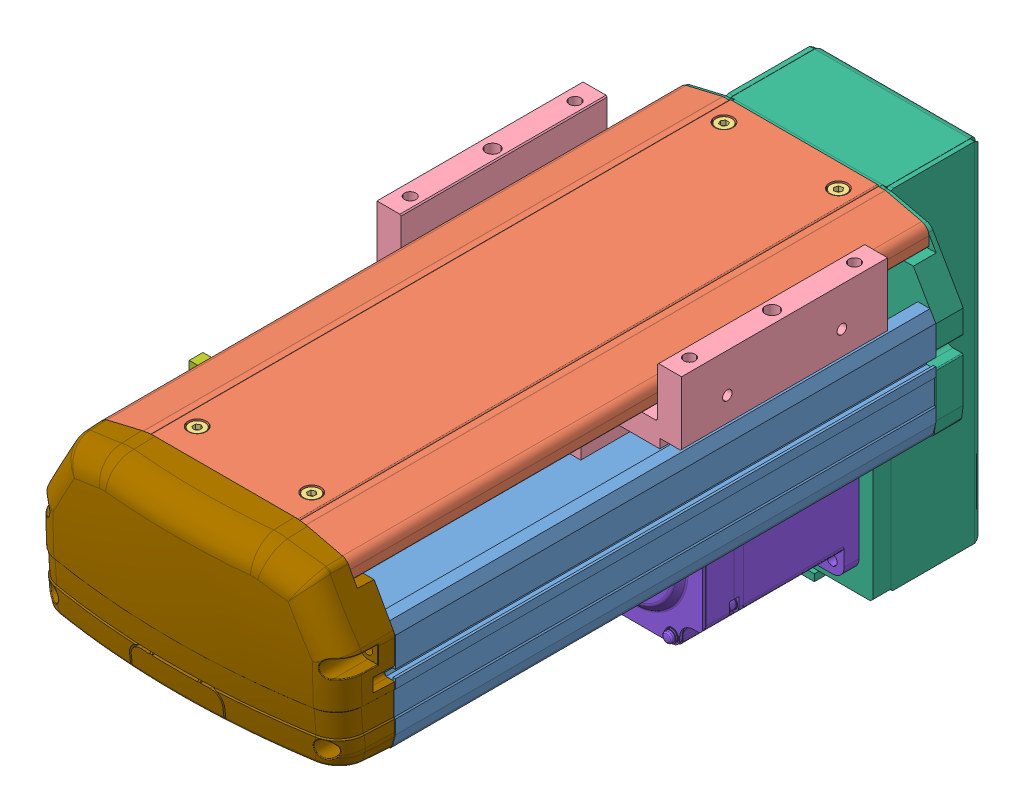
SolidWorks assembly S13-BM-200W, configuration 默认. Lengths in mm.
Overall size (190.95 160.5 348.72).
14 component instances, 9 part files, 41 mates.
Components (placement in the parent):
- S13-BL底座^S13-BM-200W-2: S13-BL底座^S13-BM-200W [默认] at origin size (135 48 259) (virtual)
- S13-BL上盖^S13-BM-200W-2: S13-BL上盖^S13-BM-200W [默认] at (0 61 116.5) size (109 12.5 253) (virtual)
- 内六角圆柱头螺钉M4×8[GB／T70．1-2000]^S13-BM-200W-5: 内六角圆柱头螺钉M4×8[GB／T70．1-2000]^S13-BM-200W [默认] at (-25 73.2 0) x (0 -1 0) z (-0.993621 0 -0.11277) size (12 7 7) (virtual)
- 内六角圆柱头螺钉M4×8[GB／T70．1-2000]^S13-BM-200W-6: 内六角圆柱头螺钉M4×8[GB／T70．1-2000]^S13-BM-200W [默认] at (25 73.2 0) x (0 -1 0) z (0.295931 0 -0.955209) size (12 7 7) (virtual)
- 内六角圆柱头螺钉M4×8[GB／T70．1-2000]^S13-BM-200W-7: 内六角圆柱头螺钉M4×8[GB／T70．1-2000]^S13-BM-200W [默认] at (-25 73.2 230) x (0 -1 0) z (0.881053 0 0.473018) size (12 7 7) (virtual)
- 内六角圆柱头螺钉M4×8[GB／T70．1-2000]^S13-BM-200W-8: 内六角圆柱头螺钉M4×8[GB／T70．1-2000]^S13-BM-200W [默认] at (25 73.2 230) x (0 -1 0) z (0.809751 0 0.586773) size (12 7 7) (virtual)
- S13-BC 滑座^S13-BM-200W-2: S13-BC 滑座^S13-BM-200W [默认] at (-1.3936 35.7784 20) size (133 62 90) (virtual)
- 复件 外置感应片ST14-17^S13-BM-200W-2: 复件 外置感应片ST14-17^S13-BM-200W [默认] at (-67.5 55 65) x (0 0 1) z (-1 0 0) size (70 30.4 7.7) (virtual)
- 复件 S13-14-BM电机板罩壳^S13-BM-200W-3: 复件 S13-14-BM电机板罩壳^S13-BM-200W [默认] at (34.6396 0 343.3649) x (-0.923728 0 0.383049) z (0 -1 0) size (129.3 86.61 155.28) (virtual)
- 复件 光电开关EE-SX672^S13-BM-200W-4: 复件 光电开关EE-SX672^S13-BM-200W [默认] at (-67.5 19.7 49) x (0 0 1) z (-1 0 0) size (26 25 13) (virtual)
- 复件 光电开关EE-SX672^S13-BM-200W-5: 复件 光电开关EE-SX672^S13-BM-200W [默认] at (-67.5 19.7 75) x (0 0 1) z (-1 0 0) size (26 25 13) (virtual)
- 复件 光电开关EE-SX672^S13-BM-200W-6: 复件 光电开关EE-SX672^S13-BM-200W [默认] at (-67.5 19.7 172) x (0 0 1) z (-1 0 0) size (26 25 13) (virtual)
- 复件 复件 松下200W电机MHMF022L1U22^S13-BM-200W-2: 复件 复件 松下200W电机MHMF022L1U22^S13-BM-200W [默认] at (0 -41.1 -4) x (0 0 -1) z (0 1 0) size (101 149.2 60) (virtual)
- 复件 13-14塑胶端盖 ^S13-BM-200W-2: 复件 13-14塑胶端盖 ^S13-BM-200W [默认] at (0 1 256) x (-1 0 0) z (0 0 -1) size (134.5 73.26 31.04) (virtual)
Mates (geometry in assembly coordinates):
- 重合169: coincident: plane of S13-BL上盖^S13-BM-200W-2 through (-25 69.2 0) normal (0 1 0); plane of 内六角圆柱头螺钉M4×8[GB／T70．1-2000]^S13-BM-200W-5 through (-25.3947 69.2 3.4777) normal (0 -1 0)
- 同心160: concentric: cylinder of 内六角圆柱头螺钉M4×8[GB／T70．1-2000]^S13-BM-200W-5 through (-25 73.2 0) axis (0 1 0) radius 3.5; cylinder of S13-BL上盖^S13-BM-200W-2 through (-25 69.2 0) axis (0 1 0) radius 4
- 同心161: concentric: cylinder of 内六角圆柱头螺钉M4×8[GB／T70．1-2000]^S13-BM-200W-6 through (25 73.2 0) axis (0 1 0) radius 3.5; cylinder of S13-BL上盖^S13-BM-200W-2 through (25 69.2 0) axis (0 1 0) radius 4
- 重合171: coincident: plane of S13-BL上盖^S13-BM-200W-2 through (25 69.2 0) normal (0 1 0); circle of 内六角圆柱头螺钉M4×8[GB／T70．1-2000]^S13-BM-200W-6
- 重合189: coincident: plane of S13-BL上盖^S13-BM-200W-2 through (25 69.2 230) normal (0 1 0); plane of 内六角圆柱头螺钉M4×8[GB／T70．1-2000]^S13-BM-200W-8 through (27.0537 69.2 227.1659) normal (0 -1 0)
- 同心192: concentric: cylinder of S13-BL上盖^S13-BM-200W-2 through (25 69.2 230) axis (0 1 0) radius 4; cylinder of 内六角圆柱头螺钉M4×8[GB／T70．1-2000]^S13-BM-200W-8 through (25 73.2 230) axis (0 1 0) radius 2
- 重合190: coincident: plane of S13-BL上盖^S13-BM-200W-2 through (-25 69.2 230) normal (0 1 0); plane of 内六角圆柱头螺钉M4×8[GB／T70．1-2000]^S13-BM-200W-7 through (-23.3444 69.2 226.9163) normal (0 -1 0)
- 同心193: concentric: cylinder of S13-BL上盖^S13-BM-200W-2 through (-25 69.2 230) axis (0 1 0) radius 4; cylinder of 内六角圆柱头螺钉M4×8[GB／T70．1-2000]^S13-BM-200W-7 through (-25 73.2 230) axis (0 1 0) radius 2
- 距离15: distance = 78 mm: plane of S13-BC 滑座^S13-BM-200W-2 through (66.5 78 20) normal (0 1 0); plane of S13-BL底座^S13-BM-200W-2 through (-65.3076 0 259) normal (0 -1 0)
- 重合205: coincident: plane of S13-BL底座^S13-BM-200W-2 through (0 0 0) normal (1 0 0); plane of S13-BL上盖^S13-BM-200W-2 through (0 61 116.5) normal (1 0 0)
- 重合228: coincident: plane of S13-BL底座^S13-BM-200W-2 through (0 0 0) normal (0 0 1); plane of assembly through (0 0 0) normal (0 0 1)
- 重合229: coincident: plane of S13-BL底座^S13-BM-200W-2 through (0 0 0) normal (0 1 0); plane of assembly through (0 0 0) normal (0 1 0)
- 重合230: coincident: plane of S13-BL底座^S13-BM-200W-2 through (0 0 0) normal (1 0 0); plane of assembly through (0 0 0) normal (1 0 0)
- 宽度3: width: plane of S13-BL底座^S13-BM-200W-2 through (67.5 43.6699 259) normal (1 0 0); plane of S13-BL底座^S13-BM-200W-2 through (-67.5 43.6699 259) normal (-1 0 0); plane of S13-BC 滑座^S13-BM-200W-2 through (-66.5 16 118.9838) normal (-1 0 0); plane of S13-BC 滑座^S13-BM-200W-2 through (66.5 16 116.7223) normal (1 0 0)
- 同心202: concentric: cylinder of S13-BL底座^S13-BM-200W-2 through (62.5 39.5 259) axis (0 0 -1) radius 1.4999; cylinder of 复件 13-14塑胶端盖 ^S13-BM-200W-2 through (62.5 39.5 236) axis (0 0 -1) radius 2.1
- 同心203: concentric: cylinder of S13-BL底座^S13-BM-200W-2 through (-62.5 39.5 259) axis (0 0 -1) radius 1.5; cylinder of 复件 13-14塑胶端盖 ^S13-BM-200W-2 through (-62.5 39.5 236) axis (0 0 -1) radius 2.1
- 重合237: coincident: plane of S13-BL底座^S13-BM-200W-2 through (-73.9407 48 236) normal (0 0 1); plane of 复件 13-14塑胶端盖 ^S13-BM-200W-2 through (0 1 236) normal (0 0 1)
- 重合238: coincident: plane of S13-BC 滑座^S13-BM-200W-2 through (-66.5 16 118.9838) normal (-1 0 0); plane of 复件 外置感应片ST14-17^S13-BM-200W-2 through (-66.5 55 65) normal (1 0 0)
- 同心204: concentric: cylinder of S13-BC 滑座^S13-BM-200W-2 through (-67 61 94) axis (-1 0 0) radius 2.1; cylinder of 复件 外置感应片ST14-17^S13-BM-200W-2 through (-67.5 61 94) axis (-1 0 0) radius 2.55
- 同心205: concentric: cylinder of S13-BC 滑座^S13-BM-200W-2 through (-67 61 44) axis (-1 0 0) radius 2.1; cylinder of 复件 外置感应片ST14-17^S13-BM-200W-2 through (-67.5 61 44) axis (-1 0 0) radius 2.55
- 宽度4: width: plane of S13-BL底座^S13-BM-200W-2 through (67.5 43.6699 259) normal (1 0 0); plane of S13-BL底座^S13-BM-200W-2 through (-67.5 43.6699 259) normal (-1 0 0); plane of 复件 S13-14-BM电机板罩壳^S13-BM-200W-3 through (-67.5 6.7616 -12) normal (-1 0 0); plane of 复件 S13-14-BM电机板罩壳^S13-BM-200W-3 through (67.5 6.7616 -12) normal (1 0 0)
- 重合239: coincident: plane of S13-BL底座^S13-BM-200W-2 through (-56.7 26.5 0) normal (0 0 -1); plane of 复件 S13-14-BM电机板罩壳^S13-BM-200W-3 through (-64.2481 2 0) normal (0 0 1)
- 重合240: coincident: plane of S13-BL底座^S13-BM-200W-2 through (32 0 259) normal (0 -1 0); plane of 复件 S13-14-BM电机板罩壳^S13-BM-200W-3 through (64.8855 0 -12) normal (0 -1 0)
- 重合241: coincident: plane of S13-BL上盖^S13-BM-200W-2 through (50.5 65.3364 -10) normal (0 0 -1); plane of 复件 S13-14-BM电机板罩壳^S13-BM-200W-3 through (0 1.7 -10) normal (0 0 1)
- 重合242: coincident: plane of S13-BL底座^S13-BM-200W-2 through (-67.5 43.6699 259) normal (-1 0 0); plane of 复件 光电开关EE-SX672^S13-BM-200W-4 through (-67.5 44.7 49) normal (1 0 0)
- 距离16: distance = 19.7 mm: plane of 复件 光电开关EE-SX672^S13-BM-200W-4 through (-80.5 19.7 49) normal (0 -1 0); plane of S13-BL底座^S13-BM-200W-2 through (-65.3076 0 259) normal (0 -1 0)
- 距离17: distance = 53 mm: plane of 复件 光电开关EE-SX672^S13-BM-200W-4 through (-80.5 19.7 49) normal (0 0 -1); plane of S13-BL底座^S13-BM-200W-2 through (-56.7 26.5 0) normal (0 0 -1)
- 重合245: coincident: plane of 复件 光电开关EE-SX672^S13-BM-200W-4 through (-80.5 44.7 49) normal (-1 0 0); plane of 复件 光电开关EE-SX672^S13-BM-200W-5 through (-80.5 44.7 75) normal (-1 0 0)
- 重合246: coincident: plane of 复件 光电开关EE-SX672^S13-BM-200W-4 through (-80.5 19.7 49) normal (0 -1 0); plane of 复件 光电开关EE-SX672^S13-BM-200W-5 through (-80.5 19.7 75) normal (0 -1 0)
- 重合247: coincident: plane of 复件 光电开关EE-SX672^S13-BM-200W-4 through (-70 32.7 65) normal (0 0 1); plane of 复件 光电开关EE-SX672^S13-BM-200W-5 through (-70 32.7 65) normal (0 0 -1)
- 宽度5: width: plane of 复件 光电开关EE-SX672^S13-BM-200W-4 through (-80.5 19.7 59) normal (0 0 1); plane of 复件 光电开关EE-SX672^S13-BM-200W-5 through (-80.5 19.7 79) normal (0 0 -1); plane of 复件 外置感应片ST14-17^S13-BM-200W-2 through (-74.2 37.6 61.5) normal (0 0 -1); plane of 复件 外置感应片ST14-17^S13-BM-200W-2 through (-74.2 53 76.5) normal (0 0 1)
- 距离18: distance = 58 mm: plane of 复件 光电开关EE-SX672^S13-BM-200W-6 through (-80.5 19.7 178) normal (0 0 1); plane of S13-BL底座^S13-BM-200W-2 through (-73.9407 48 236) normal (0 0 1)
- 重合249: coincident: plane of 复件 光电开关EE-SX672^S13-BM-200W-5 through (-80.5 19.7 75) normal (0 -1 0); plane of 复件 光电开关EE-SX672^S13-BM-200W-6 through (-80.5 19.7 172) normal (0 -1 0)
- 重合250: coincident: plane of 复件 光电开关EE-SX672^S13-BM-200W-5 through (-80.5 44.7 75) normal (-1 0 0); plane of 复件 光电开关EE-SX672^S13-BM-200W-6 through (-80.5 44.7 172) normal (-1 0 0)
- 重合255: coincident: plane of 复件 S13-14-BM电机板罩壳^S13-BM-200W-3 through (0 1.7 -4) normal (0 0 1); plane of 复件 复件 松下200W电机MHMF022L1U22^S13-BM-200W-2 through (-25 -16.1 -4) normal (0 0 -1)
- 宽度8: width: plane of 复件 S13-14-BM电机板罩壳^S13-BM-200W-3 through (-36 -79.5 -12) normal (-1 0 0); plane of 复件 S13-14-BM电机板罩壳^S13-BM-200W-3 through (36 -79.5 -12) normal (1 0 0); plane of 复件 复件 松下200W电机MHMF022L1U22^S13-BM-200W-2 through (-30 -66.1 50.5) normal (-1 0 0); plane of 复件 复件 松下200W电机MHMF022L1U22^S13-BM-200W-2 through (30 -16.1 50.5) normal (1 0 0)
- 距离21: distance = 30 mm: plane of 复件 复件 松下200W电机MHMF022L1U22^S13-BM-200W-2 through (25 -71.1 50.5) normal (0 -1 0); moEndPointRef_w of 复件 S13-14-BM电机板罩壳^S13-BM-200W-3
- 距离22: distance = 117 mm: plane of 复件 S13-14-BM电机板罩壳^S13-BM-200W-3 through (0 -3.5 -52) normal (0 0 -1); cylinder of S13-BC 滑座^S13-BM-200W-2 through (-61 78 65) axis (0 1 0) radius 3
- 同心206: concentric: cylinder of S13-BC 滑座^S13-BM-200W-2 through (-67 61 40) axis (-1 0 0) radius 2.1; cylinder of 复件 外置感应片ST14-17^S13-BM-200W-2 through (-67.5 61 40) axis (-1 0 0) radius 2.55
- 同心207: concentric: cylinder of S13-BC 滑座^S13-BM-200W-2 through (-67 61 90) axis (-1 0 0) radius 2.1; cylinder of 复件 外置感应片ST14-17^S13-BM-200W-2 through (-67.5 61 90) axis (-1 0 0) radius 2.55
- 宽度9: width: plane of 复件 光电开关EE-SX672^S13-BM-200W-5 through (-80.5 19.7 75) normal (0 0 -1); plane of 复件 光电开关EE-SX672^S13-BM-200W-4 through (-80.5 19.7 55) normal (0 0 1); plane of 复件 外置感应片ST14-17^S13-BM-200W-2 through (-74.2 53 72.5) normal (0 0 1); plane of 复件 外置感应片ST14-17^S13-BM-200W-2 through (-74.2 37.6 57.5) normal (0 0 -1)
